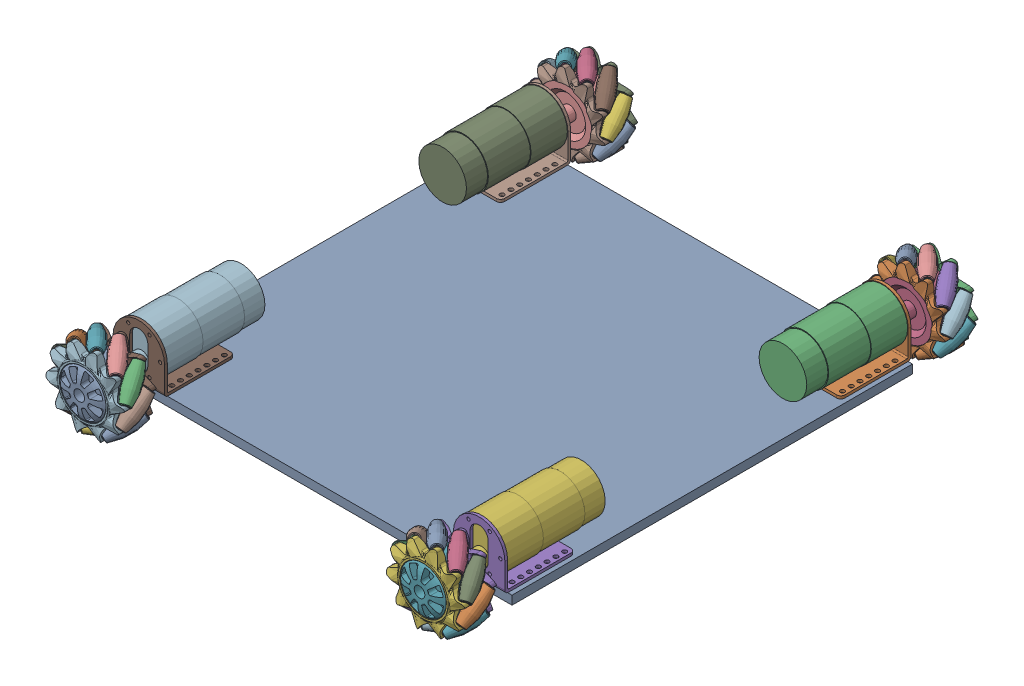
SolidWorks assembly ChassisAssembly, configuration Default. Lengths in mm.
Overall size (327.06 78.93 384.81).
17 component instances, 4 part files, 12 mates.
Components (placement in the parent):
- MainPlatform-1: MainPlatform [Default] at origin size (292.1 6.35 292.1)
- MecanumWMotor-1: MecanumWMotor [Default] at (124.1 6.35 -148.1) x (0 0 1) z (-1 0 0) size (118.9 78.93 78.86)
  - 37D bracket -1: 37D bracket  [Default] at origin size (51.2 39.6 37.6)
  - Motor - 37D - with encoder - 100_1 and 131_1-1: Motor - 37D - with encoder - 100_1 and 131_1 [Default] at (74.6 20.8 0) x (0 0 1) z (-1 0 0) size (36.8 36.8 94.6)
  - Mecanum Wheel Right-1: Mecanum Wheel Right [Default] at (-8.3271 45.8337 -42.2568) x (1 0 0) z (0 -0.351292 0.936266) size (34.3 61.34 61.21)
- MecanumWMotor-2: MecanumWMotor [Default] at (124.1 6.35 148.1) x (0 0 -1) z (1 0 0) size (118.9 78.93 78.86)
  - 37D bracket -1: 37D bracket  [Default] at origin size (51.2 39.6 37.6)
  - Motor - 37D - with encoder - 100_1 and 131_1-1: Motor - 37D - with encoder - 100_1 and 131_1 [Default] at (74.6 20.8 0) x (0 0 1) z (-1 0 0) size (36.8 36.8 94.6)
  - Mecanum Wheel Right-1: Mecanum Wheel Right [Default] at (-8.3271 45.8337 -42.2568) x (1 0 0) z (0 -0.351292 0.936266) size (34.3 61.34 61.21)
- MecanumWMotor-4: MecanumWMotor [Default] at (-124.1 6.35 -148.1) x (0 0 1) z (-1 0 0) size (118.9 78.93 78.86)
  - 37D bracket -1: 37D bracket  [Default] at origin size (51.2 39.6 37.6)
  - Motor - 37D - with encoder - 100_1 and 131_1-1: Motor - 37D - with encoder - 100_1 and 131_1 [Default] at (74.6 20.8 0) x (0 0 1) z (-1 0 0) size (36.8 36.8 94.6)
  - Mecanum Wheel Right-1: Mecanum Wheel Right [Default] at (-8.3271 45.8337 -42.2568) x (1 0 0) z (0 -0.351292 0.936266) size (34.3 61.34 61.21)
- MecanumWMotor-5: MecanumWMotor [Default] at (-124.1 6.35 148.1) x (0 0 -1) z (1 0 0) size (118.9 78.93 78.86)
  - 37D bracket -1: 37D bracket  [Default] at origin size (51.2 39.6 37.6)
  - Motor - 37D - with encoder - 100_1 and 131_1-1: Motor - 37D - with encoder - 100_1 and 131_1 [Default] at (74.6 20.8 0) x (0 0 1) z (-1 0 0) size (36.8 36.8 94.6)
  - Mecanum Wheel Right-1: Mecanum Wheel Right [Default] at (-8.3271 45.8337 -42.2568) x (1 0 0) z (0 -0.351292 0.936266) size (34.3 61.34 61.21)
Mates (geometry in assembly coordinates):
- Coincident6: coincident anti-aligned: plane of MainPlatform-1 through (0 6.35 0) normal (0 1 0); plane of MecanumWMotor-1/37D bracket -1 through (105.3 6.35 -145.6) normal (0 -1 0)
- Concentric5: concentric aligned: cylinder of MainPlatform-1 through (139.7 0 -139.7) axis (0 1 0) radius 1.6; circle of MecanumWMotor-1/37D bracket -1
- Concentric9: concentric aligned: circle of MainPlatform-1; cylinder of MecanumWMotor-1/37D bracket -1 through (108.5 8.35 -101.3) axis (0 1 0) radius 1.6
- Concentric10: concentric aligned: cylinder of MainPlatform-1 through (-139.7 0 -139.7) axis (0 1 0) radius 1.6; circle of MecanumWMotor-4/37D bracket -1
- Coincident11: coincident anti-aligned: plane of MainPlatform-1 through (0 6.35 0) normal (0 1 0); plane of MecanumWMotor-4/37D bracket -1 through (-142.9 6.35 -145.6) normal (0 -1 0)
- Concentric11: concentric aligned: cylinder of MainPlatform-1 through (-108.5 0 -101.3) axis (0 1 0) radius 1.6; cylinder of MecanumWMotor-4/37D bracket -1 through (-108.5 8.35 -101.3) axis (0 1 0) radius 1.6
- Concentric12: concentric aligned: cylinder of MainPlatform-1 through (139.7 0 101.3) axis (0 1 0) radius 1.6; cylinder of MecanumWMotor-2/37D bracket -1 through (139.7 8.35 101.3) axis (0 1 0) radius 1.6
- Concentric13: concentric aligned: cylinder of MainPlatform-1 through (108.5 0 139.7) axis (0 1 0) radius 1.6; cylinder of MecanumWMotor-2/37D bracket -1 through (108.5 8.35 139.7) axis (0 1 0) radius 1.6
- Coincident12: coincident anti-aligned: plane of MainPlatform-1 through (0 6.35 0) normal (0 1 0); plane of MecanumWMotor-2/37D bracket -1 through (142.9 6.35 145.6) normal (0 -1 0)
- Concentric16: concentric: cylinder of MainPlatform-1 through (-108.5 0 101.3) axis (0 1 0) radius 1.6; cylinder of MecanumWMotor-5/37D bracket -1 through (-108.5 8.35 101.3) axis (0 1 0) radius 1.6
- Concentric17: concentric: cylinder of MainPlatform-1 through (-139.7 0 139.7) axis (0 1 0) radius 1.6; cylinder of MecanumWMotor-5/37D bracket -1 through (-139.7 8.35 139.7) axis (0 1 0) radius 1.6
- Coincident13: coincident anti-aligned: plane of MainPlatform-1 through (0 6.35 0) normal (0 1 0); plane of MecanumWMotor-5/37D bracket -1 through (-105.3 6.35 145.6) normal (0 -1 0)
